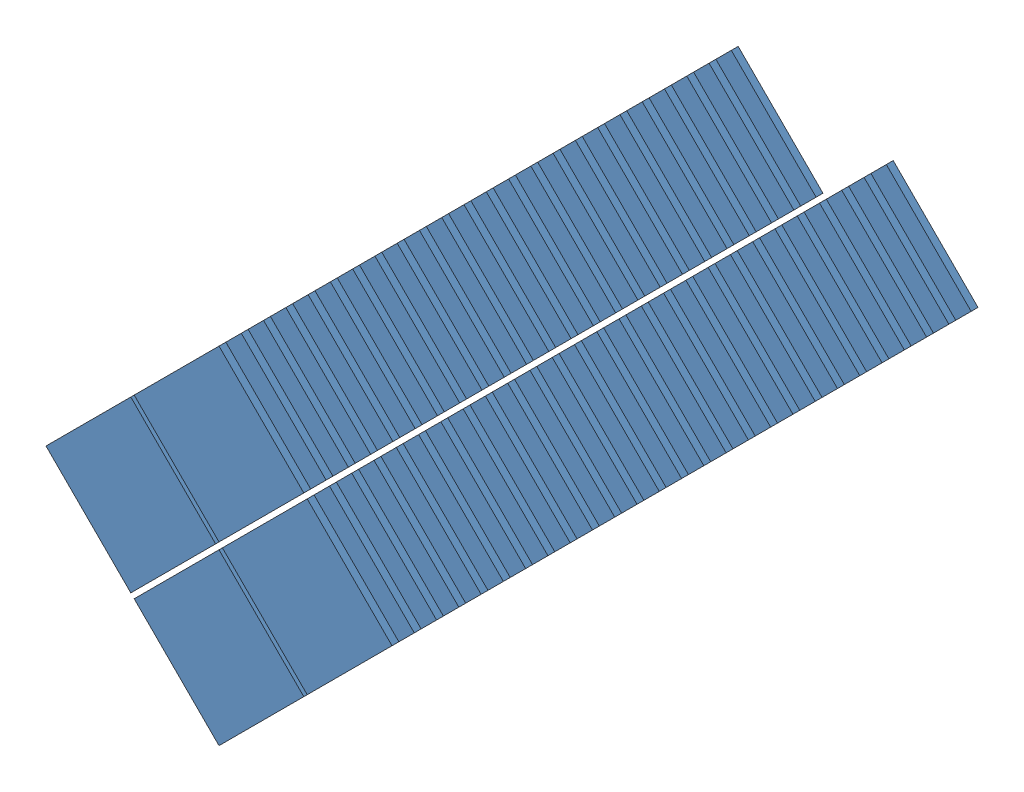
SolidWorks assembly Sprite Installation, configuration Default. Lengths in mm.
Overall size (100.97 100.97 171).
102 component instances, 1 part files, 0 mates.
Components (placement in the parent):
- Sprites-1: Sprites [Default] at (69.4082 -74.6969 276.5389) x (0.707107 -0.707107 0) z (-0.707107 -0.707107 0) size (35 2 35)
- Sprites-2: Sprites [Default] at (95.1469 -48.9582 276.5389) x (0.707107 -0.707107 0) z (-0.707107 -0.707107 0) size (35 2 35)
- Sprites-3: Sprites [Default] at (95.1469 -100.4356 276.5389) x (0.707107 -0.707107 0) z (-0.707107 -0.707107 0) size (35 2 35)
- Sprites-4: Sprites [Default] at (120.8856 -74.6969 276.5389) x (0.707107 -0.707107 0) z (-0.707107 -0.707107 0) size (35 2 35)
- Sprites-5: Sprites [Default] at (95.1469 -48.9582 270.0389) x (0.707107 -0.707107 0) z (-0.707107 -0.707107 0) size (35 2 35)
- Sprites-6: Sprites [Default] at (95.1469 -48.9582 263.5389) x (0.707107 -0.707107 0) z (-0.707107 -0.707107 0) size (35 2 35)
- Sprites-7: Sprites [Default] at (95.1469 -48.9582 257.0389) x (0.707107 -0.707107 0) z (-0.707107 -0.707107 0) size (35 2 35)
- Sprites-8: Sprites [Default] at (95.1469 -48.9582 250.5389) x (0.707107 -0.707107 0) z (-0.707107 -0.707107 0) size (35 2 35)
- Sprites-9: Sprites [Default] at (95.1469 -48.9582 244.0389) x (0.707107 -0.707107 0) z (-0.707107 -0.707107 0) size (35 2 35)
- Sprites-10: Sprites [Default] at (95.1469 -48.9582 237.5389) x (0.707107 -0.707107 0) z (-0.707107 -0.707107 0) size (35 2 35)
- Sprites-11: Sprites [Default] at (95.1469 -48.9582 231.0389) x (0.707107 -0.707107 0) z (-0.707107 -0.707107 0) size (35 2 35)
- Sprites-12: Sprites [Default] at (95.1469 -48.9582 224.5389) x (0.707107 -0.707107 0) z (-0.707107 -0.707107 0) size (35 2 35)
- Sprites-13: Sprites [Default] at (95.1469 -48.9582 218.0389) x (0.707107 -0.707107 0) z (-0.707107 -0.707107 0) size (35 2 35)
- Sprites-14: Sprites [Default] at (95.1469 -48.9582 211.5389) x (0.707107 -0.707107 0) z (-0.707107 -0.707107 0) size (35 2 35)
- Sprites-15: Sprites [Default] at (95.1469 -48.9582 205.0389) x (0.707107 -0.707107 0) z (-0.707107 -0.707107 0) size (35 2 35)
- Sprites-16: Sprites [Default] at (95.1469 -48.9582 198.5389) x (0.707107 -0.707107 0) z (-0.707107 -0.707107 0) size (35 2 35)
- Sprites-17: Sprites [Default] at (95.1469 -48.9582 192.0389) x (0.707107 -0.707107 0) z (-0.707107 -0.707107 0) size (35 2 35)
- Sprites-18: Sprites [Default] at (95.1469 -48.9582 185.5389) x (0.707107 -0.707107 0) z (-0.707107 -0.707107 0) size (35 2 35)
- Sprites-19: Sprites [Default] at (95.1469 -48.9582 179.0389) x (0.707107 -0.707107 0) z (-0.707107 -0.707107 0) size (35 2 35)
- Sprites-20: Sprites [Default] at (95.1469 -48.9582 172.5389) x (0.707107 -0.707107 0) z (-0.707107 -0.707107 0) size (35 2 35)
- Sprites-21: Sprites [Default] at (95.1469 -48.9582 166.0389) x (0.707107 -0.707107 0) z (-0.707107 -0.707107 0) size (35 2 35)
- Sprites-22: Sprites [Default] at (95.1469 -48.9582 159.5389) x (0.707107 -0.707107 0) z (-0.707107 -0.707107 0) size (35 2 35)
- Sprites-23: Sprites [Default] at (95.1469 -48.9582 153.0389) x (0.707107 -0.707107 0) z (-0.707107 -0.707107 0) size (35 2 35)
- Sprites-24: Sprites [Default] at (95.1469 -48.9582 146.5389) x (0.707107 -0.707107 0) z (-0.707107 -0.707107 0) size (35 2 35)
- Sprites-25: Sprites [Default] at (95.1469 -48.9582 140.0389) x (0.707107 -0.707107 0) z (-0.707107 -0.707107 0) size (35 2 35)
- Sprites-26: Sprites [Default] at (95.1469 -48.9582 133.5389) x (0.707107 -0.707107 0) z (-0.707107 -0.707107 0) size (35 2 35)
- Sprites-27: Sprites [Default] at (95.1469 -48.9582 127.0389) x (0.707107 -0.707107 0) z (-0.707107 -0.707107 0) size (35 2 35)
- Sprites-28: Sprites [Default] at (95.1469 -100.4356 270.0389) x (0.707107 -0.707107 0) z (-0.707107 -0.707107 0) size (35 2 35)
- Sprites-29: Sprites [Default] at (95.1469 -100.4356 263.5389) x (0.707107 -0.707107 0) z (-0.707107 -0.707107 0) size (35 2 35)
- Sprites-30: Sprites [Default] at (95.1469 -100.4356 257.0389) x (0.707107 -0.707107 0) z (-0.707107 -0.707107 0) size (35 2 35)
- Sprites-31: Sprites [Default] at (95.1469 -100.4356 250.5389) x (0.707107 -0.707107 0) z (-0.707107 -0.707107 0) size (35 2 35)
- Sprites-32: Sprites [Default] at (95.1469 -100.4356 244.0389) x (0.707107 -0.707107 0) z (-0.707107 -0.707107 0) size (35 2 35)
- Sprites-33: Sprites [Default] at (95.1469 -100.4356 237.5389) x (0.707107 -0.707107 0) z (-0.707107 -0.707107 0) size (35 2 35)
- Sprites-34: Sprites [Default] at (95.1469 -100.4356 231.0389) x (0.707107 -0.707107 0) z (-0.707107 -0.707107 0) size (35 2 35)
- Sprites-35: Sprites [Default] at (95.1469 -100.4356 224.5389) x (0.707107 -0.707107 0) z (-0.707107 -0.707107 0) size (35 2 35)
- Sprites-36: Sprites [Default] at (95.1469 -100.4356 218.0389) x (0.707107 -0.707107 0) z (-0.707107 -0.707107 0) size (35 2 35)
- Sprites-37: Sprites [Default] at (95.1469 -100.4356 211.5389) x (0.707107 -0.707107 0) z (-0.707107 -0.707107 0) size (35 2 35)
- Sprites-38: Sprites [Default] at (95.1469 -100.4356 205.0389) x (0.707107 -0.707107 0) z (-0.707107 -0.707107 0) size (35 2 35)
- Sprites-39: Sprites [Default] at (95.1469 -100.4356 198.5389) x (0.707107 -0.707107 0) z (-0.707107 -0.707107 0) size (35 2 35)
- Sprites-40: Sprites [Default] at (95.1469 -100.4356 192.0389) x (0.707107 -0.707107 0) z (-0.707107 -0.707107 0) size (35 2 35)
- Sprites-41: Sprites [Default] at (95.1469 -100.4356 185.5389) x (0.707107 -0.707107 0) z (-0.707107 -0.707107 0) size (35 2 35)
- Sprites-42: Sprites [Default] at (95.1469 -100.4356 179.0389) x (0.707107 -0.707107 0) z (-0.707107 -0.707107 0) size (35 2 35)
- Sprites-43: Sprites [Default] at (95.1469 -100.4356 172.5389) x (0.707107 -0.707107 0) z (-0.707107 -0.707107 0) size (35 2 35)
- Sprites-44: Sprites [Default] at (95.1469 -100.4356 166.0389) x (0.707107 -0.707107 0) z (-0.707107 -0.707107 0) size (35 2 35)
- Sprites-45: Sprites [Default] at (95.1469 -100.4356 159.5389) x (0.707107 -0.707107 0) z (-0.707107 -0.707107 0) size (35 2 35)
- Sprites-46: Sprites [Default] at (95.1469 -100.4356 153.0389) x (0.707107 -0.707107 0) z (-0.707107 -0.707107 0) size (35 2 35)
- Sprites-47: Sprites [Default] at (95.1469 -100.4356 146.5389) x (0.707107 -0.707107 0) z (-0.707107 -0.707107 0) size (35 2 35)
- Sprites-48: Sprites [Default] at (95.1469 -100.4356 140.0389) x (0.707107 -0.707107 0) z (-0.707107 -0.707107 0) size (35 2 35)
- Sprites-49: Sprites [Default] at (95.1469 -100.4356 133.5389) x (0.707107 -0.707107 0) z (-0.707107 -0.707107 0) size (35 2 35)
- Sprites-50: Sprites [Default] at (95.1469 -100.4356 127.0389) x (0.707107 -0.707107 0) z (-0.707107 -0.707107 0) size (35 2 35)
- Sprites-51: Sprites [Default] at (120.8856 -74.6969 270.0389) x (0.707107 -0.707107 0) z (-0.707107 -0.707107 0) size (35 2 35)
- Sprites-52: Sprites [Default] at (120.8856 -74.6969 263.5389) x (0.707107 -0.707107 0) z (-0.707107 -0.707107 0) size (35 2 35)
- Sprites-53: Sprites [Default] at (120.8856 -74.6969 257.0389) x (0.707107 -0.707107 0) z (-0.707107 -0.707107 0) size (35 2 35)
- Sprites-54: Sprites [Default] at (120.8856 -74.6969 250.5389) x (0.707107 -0.707107 0) z (-0.707107 -0.707107 0) size (35 2 35)
- Sprites-55: Sprites [Default] at (120.8856 -74.6969 244.0389) x (0.707107 -0.707107 0) z (-0.707107 -0.707107 0) size (35 2 35)
- Sprites-56: Sprites [Default] at (120.8856 -74.6969 237.5389) x (0.707107 -0.707107 0) z (-0.707107 -0.707107 0) size (35 2 35)
- Sprites-57: Sprites [Default] at (120.8856 -74.6969 231.0389) x (0.707107 -0.707107 0) z (-0.707107 -0.707107 0) size (35 2 35)
- Sprites-58: Sprites [Default] at (120.8856 -74.6969 224.5389) x (0.707107 -0.707107 0) z (-0.707107 -0.707107 0) size (35 2 35)
- Sprites-59: Sprites [Default] at (120.8856 -74.6969 218.0389) x (0.707107 -0.707107 0) z (-0.707107 -0.707107 0) size (35 2 35)
- Sprites-60: Sprites [Default] at (120.8856 -74.6969 211.5389) x (0.707107 -0.707107 0) z (-0.707107 -0.707107 0) size (35 2 35)
- Sprites-61: Sprites [Default] at (120.8856 -74.6969 205.0389) x (0.707107 -0.707107 0) z (-0.707107 -0.707107 0) size (35 2 35)
- Sprites-62: Sprites [Default] at (120.8856 -74.6969 198.5389) x (0.707107 -0.707107 0) z (-0.707107 -0.707107 0) size (35 2 35)
- Sprites-63: Sprites [Default] at (120.8856 -74.6969 192.0389) x (0.707107 -0.707107 0) z (-0.707107 -0.707107 0) size (35 2 35)
- Sprites-64: Sprites [Default] at (120.8856 -74.6969 185.5389) x (0.707107 -0.707107 0) z (-0.707107 -0.707107 0) size (35 2 35)
- Sprites-65: Sprites [Default] at (120.8856 -74.6969 179.0389) x (0.707107 -0.707107 0) z (-0.707107 -0.707107 0) size (35 2 35)
- Sprites-66: Sprites [Default] at (120.8856 -74.6969 172.5389) x (0.707107 -0.707107 0) z (-0.707107 -0.707107 0) size (35 2 35)
- Sprites-67: Sprites [Default] at (120.8856 -74.6969 166.0389) x (0.707107 -0.707107 0) z (-0.707107 -0.707107 0) size (35 2 35)
- Sprites-68: Sprites [Default] at (120.8856 -74.6969 159.5389) x (0.707107 -0.707107 0) z (-0.707107 -0.707107 0) size (35 2 35)
- Sprites-69: Sprites [Default] at (120.8856 -74.6969 153.0389) x (0.707107 -0.707107 0) z (-0.707107 -0.707107 0) size (35 2 35)
- Sprites-70: Sprites [Default] at (120.8856 -74.6969 146.5389) x (0.707107 -0.707107 0) z (-0.707107 -0.707107 0) size (35 2 35)
- Sprites-71: Sprites [Default] at (120.8856 -74.6969 140.0389) x (0.707107 -0.707107 0) z (-0.707107 -0.707107 0) size (35 2 35)
- Sprites-72: Sprites [Default] at (120.8856 -74.6969 133.5389) x (0.707107 -0.707107 0) z (-0.707107 -0.707107 0) size (35 2 35)
- Sprites-73: Sprites [Default] at (120.8856 -74.6969 127.0389) x (0.707107 -0.707107 0) z (-0.707107 -0.707107 0) size (35 2 35)
- Sprites-74: Sprites [Default] at (120.8856 -74.6969 120.5389) x (0.707107 -0.707107 0) z (-0.707107 -0.707107 0) size (35 2 35)
- Sprites-75: Sprites [Default] at (120.8856 -74.6969 114.0389) x (0.707107 -0.707107 0) z (-0.707107 -0.707107 0) size (35 2 35)
- Sprites-76: Sprites [Default] at (120.8856 -74.6969 107.5389) x (0.707107 -0.707107 0) z (-0.707107 -0.707107 0) size (35 2 35)
- Sprites-77: Sprites [Default] at (69.4082 -74.6969 270.0389) x (0.707107 -0.707107 0) z (-0.707107 -0.707107 0) size (35 2 35)
- Sprites-78: Sprites [Default] at (69.4082 -74.6969 263.5389) x (0.707107 -0.707107 0) z (-0.707107 -0.707107 0) size (35 2 35)
- Sprites-79: Sprites [Default] at (69.4082 -74.6969 257.0389) x (0.707107 -0.707107 0) z (-0.707107 -0.707107 0) size (35 2 35)
- Sprites-80: Sprites [Default] at (69.4082 -74.6969 250.5389) x (0.707107 -0.707107 0) z (-0.707107 -0.707107 0) size (35 2 35)
- Sprites-81: Sprites [Default] at (69.4082 -74.6969 244.0389) x (0.707107 -0.707107 0) z (-0.707107 -0.707107 0) size (35 2 35)
- Sprites-82: Sprites [Default] at (69.4082 -74.6969 237.5389) x (0.707107 -0.707107 0) z (-0.707107 -0.707107 0) size (35 2 35)
- Sprites-83: Sprites [Default] at (69.4082 -74.6969 231.0389) x (0.707107 -0.707107 0) z (-0.707107 -0.707107 0) size (35 2 35)
- Sprites-84: Sprites [Default] at (69.4082 -74.6969 224.5389) x (0.707107 -0.707107 0) z (-0.707107 -0.707107 0) size (35 2 35)
- Sprites-85: Sprites [Default] at (69.4082 -74.6969 218.0389) x (0.707107 -0.707107 0) z (-0.707107 -0.707107 0) size (35 2 35)
- Sprites-86: Sprites [Default] at (69.4082 -74.6969 211.5389) x (0.707107 -0.707107 0) z (-0.707107 -0.707107 0) size (35 2 35)
- Sprites-87: Sprites [Default] at (69.4082 -74.6969 205.0389) x (0.707107 -0.707107 0) z (-0.707107 -0.707107 0) size (35 2 35)
- Sprites-88: Sprites [Default] at (69.4082 -74.6969 198.5389) x (0.707107 -0.707107 0) z (-0.707107 -0.707107 0) size (35 2 35)
- Sprites-89: Sprites [Default] at (69.4082 -74.6969 192.0389) x (0.707107 -0.707107 0) z (-0.707107 -0.707107 0) size (35 2 35)
- Sprites-90: Sprites [Default] at (69.4082 -74.6969 185.5389) x (0.707107 -0.707107 0) z (-0.707107 -0.707107 0) size (35 2 35)
- Sprites-91: Sprites [Default] at (69.4082 -74.6969 179.0389) x (0.707107 -0.707107 0) z (-0.707107 -0.707107 0) size (35 2 35)
- Sprites-92: Sprites [Default] at (69.4082 -74.6969 172.5389) x (0.707107 -0.707107 0) z (-0.707107 -0.707107 0) size (35 2 35)
- Sprites-93: Sprites [Default] at (69.4082 -74.6969 166.0389) x (0.707107 -0.707107 0) z (-0.707107 -0.707107 0) size (35 2 35)
- Sprites-94: Sprites [Default] at (69.4082 -74.6969 159.5389) x (0.707107 -0.707107 0) z (-0.707107 -0.707107 0) size (35 2 35)
- Sprites-95: Sprites [Default] at (69.4082 -74.6969 153.0389) x (0.707107 -0.707107 0) z (-0.707107 -0.707107 0) size (35 2 35)
- Sprites-96: Sprites [Default] at (69.4082 -74.6969 146.5389) x (0.707107 -0.707107 0) z (-0.707107 -0.707107 0) size (35 2 35)
- Sprites-97: Sprites [Default] at (69.4082 -74.6969 140.0389) x (0.707107 -0.707107 0) z (-0.707107 -0.707107 0) size (35 2 35)
- Sprites-98: Sprites [Default] at (69.4082 -74.6969 133.5389) x (0.707107 -0.707107 0) z (-0.707107 -0.707107 0) size (35 2 35)
- Sprites-99: Sprites [Default] at (69.4082 -74.6969 127.0389) x (0.707107 -0.707107 0) z (-0.707107 -0.707107 0) size (35 2 35)
- Sprites-100: Sprites [Default] at (69.4082 -74.6969 120.5389) x (0.707107 -0.707107 0) z (-0.707107 -0.707107 0) size (35 2 35)
- Sprites-101: Sprites [Default] at (69.4082 -74.6969 114.0389) x (0.707107 -0.707107 0) z (-0.707107 -0.707107 0) size (35 2 35)
- Sprites-102: Sprites [Default] at (69.4082 -74.6969 107.5389) x (0.707107 -0.707107 0) z (-0.707107 -0.707107 0) size (35 2 35)
